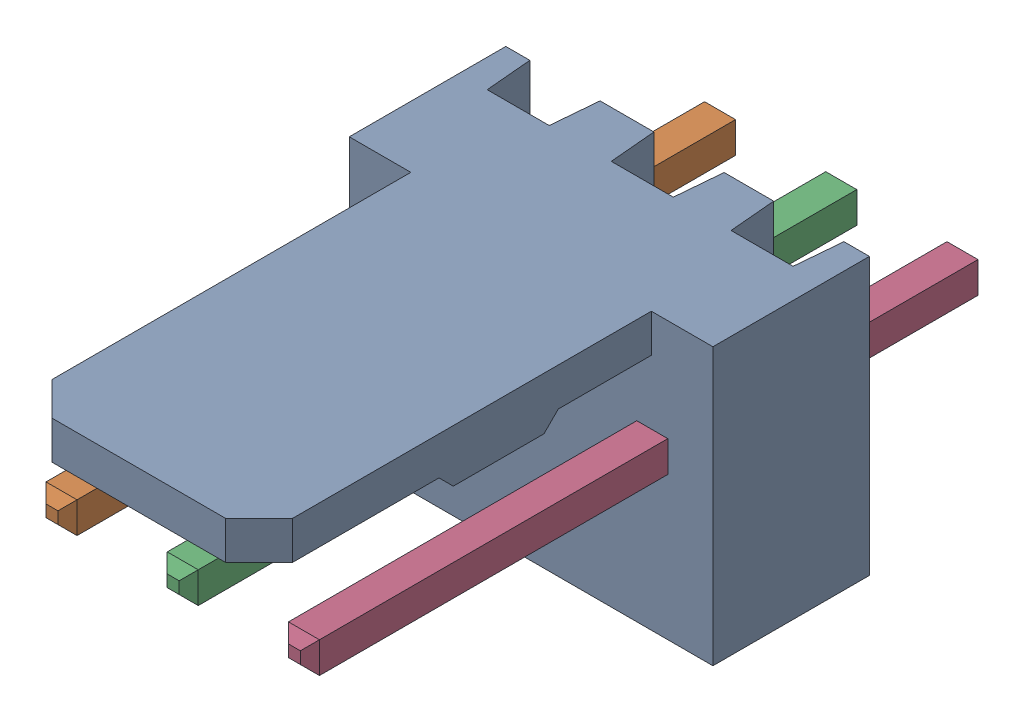
SolidWorks assembly Molex PCB 3 pin v2 v6, configuration Default. Lengths in mm.
Overall size (7.62 5.79 14.92).
4 component instances, 2 part files, 0 mates.
Components (placement in the parent):
- BASE9710016_2-1: BASE9710016_2 [Default] at (2.54 2.895 -8.22) size (7.62 5.79 11.5)
- PINO9710016_2-1: PINO9710016_2 [Default] at (1.27 3.325 -0.72) size (0.65 0.65 14.2)
- PINO9710016_2-2: PINO9710016_2 [Default] at (3.81 3.325 -0.72) size (0.65 0.65 14.2)
- PINO9710016_2-3: PINO9710016_2 [Default] at (6.35 3.325 -0.72) size (0.65 0.65 14.2)
